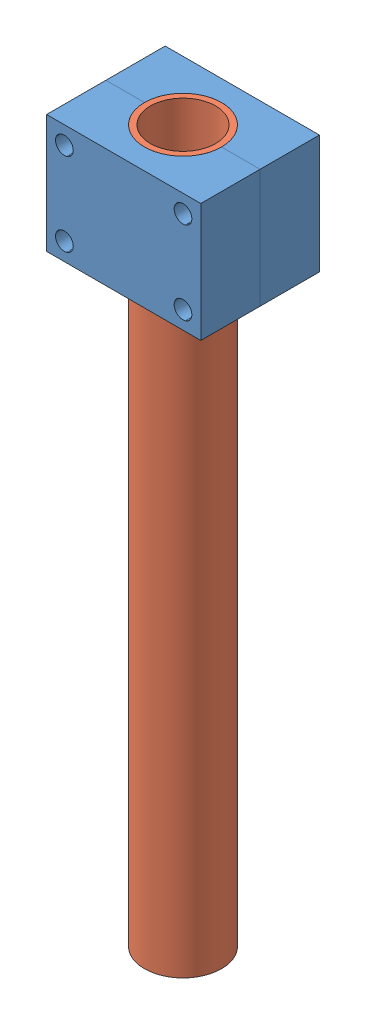
SolidWorks assembly Cụm-gá, configuration Default. Lengths in mm.
Overall size (26 120 20).
3 component instances, 2 part files, 6 mates.
Components (placement in the parent):
- FPV_do-ga-1: FPV_do-ga [Default] at (-5.5337 4.1589 26.5614) size (26 20 10)
- FPV_Arm-1: FPV_Arm [Default] at (7.4663 -95.8411 26.5614) size (13 120 13)
- FPV_do-ga-2: FPV_do-ga [Default] at (-5.5337 24.1589 26.5614) x (1 0 0) z (0 0 -1) size (26 20 10)
Mates (geometry in assembly coordinates):
- Coincident1: coincident anti-aligned: plane of FPV_do-ga-1 through (-5.5337 24.1589 26.5614) normal (0 0 1); plane of FPV_do-ga-2 through (-5.5337 4.1589 26.5614) normal (0 0 -1)
- Coincident2: coincident aligned: plane of FPV_do-ga-1 through (-5.5337 4.1589 26.5614) normal (0 -1 0); plane of FPV_do-ga-2 through (-5.5337 4.1589 26.5614) normal (0 -1 0)
- Coincident3: coincident aligned: plane of FPV_do-ga-1 through (-5.5337 24.1589 26.5614) normal (-1 0 0); plane of FPV_do-ga-2 through (-5.5337 4.1589 26.5614) normal (-1 0 0)
- Concentric1: concentric anti-aligned: cylinder of FPV_do-ga-1 through (7.4663 4.1589 26.5614) axis (0 1 0) radius 6.5; cylinder of FPV_Arm-1 through (7.4663 24.1589 26.5614) axis (0 -1 0) radius 6.5
- Coincident4: coincident aligned: plane of FPV_do-ga-1 through (-5.5337 24.1589 26.5614) normal (0 1 0); plane of FPV_Arm-1 through (7.4663 24.1589 26.5614) normal (0 1 0)
- Coincident5: coincident aligned: plane of FPV_Arm-1 through (7.4663 24.1589 26.5614) normal (0 1 0); plane of FPV_do-ga-2 through (-5.5337 24.1589 26.5614) normal (0 1 0)
